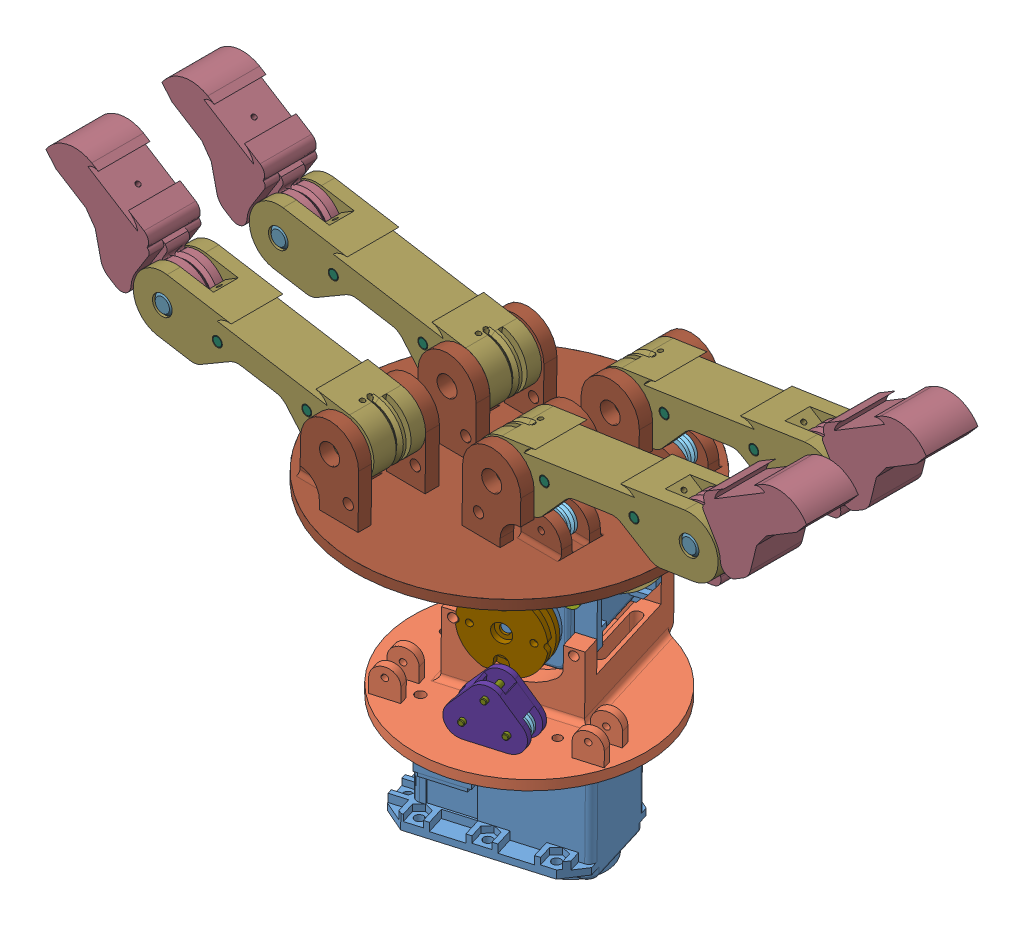
SolidWorks assembly OpenHand_v2.6, configuration 默认. Lengths in mm.
Overall size (235.63 168.54 102.71).
62 component instances, 17 part files, 48 mates.
Components (placement in the parent):
- dynamixel MX-28-1: dynamixel MX-28 [Back Off] at (-35.2758 -22.644 76.0254) x (-0.956254 0.00984 0.292372) z (0.292356 -0.003009 0.956305) size (35.6 50.71 42.77)
- 手爪手臂连接件-1: 手爪手臂连接件 [默认] at (-31.7883 -47.1811 88.258) x (0.956254 -0.00984 -0.292372) z (0.01029 0.999947 0) size (72 72 25.25)
- 手爪连接滑轮组-1: 手爪连接滑轮组 [默认] at (-84.7153 10.6727 102.6786) x (0 0.011926 -0.999929) z (1 0 0) size (37.98 14.28 12.7)
  - my_b3_t-1: my_b3_t [默认] at (-6.5452 0.3026 30) size (37.98 14.28 8.2)
  - my_b3_t-2: my_b3_t [默认] at (-6.5452 0.3026 24.7) x (-1 0 0) z (0 0 -1) size (37.98 14.28 8.2)
  - 连接销L12-4: 连接销L12 [默认] at (-20.5452 0.3787 28.3573) x (0 0 -1) z (1 0 0) size (12 1.8 1.8)
  - 连接销L12-5: 连接销L12 [默认] at (-6.5452 -6.5319 28.3573) x (0 0 -1) z (1 0 0) size (12 1.8 1.8)
  - 连接销L12-6: 连接销L12 [默认] at (7.4531 0.3475 26.3427) x (0 0 1) z (1 0 0) size (12 1.8 1.8)
  - pulley-5: pulley [默认] at (7.4531 0.3475 27.15) x (0 1 0) z (1 0 0) size (8 4.9 8)
  - pulley-6: pulley [默认] at (-20.5452 0.3787 27.15) x (0 1 0) z (1 0 0) size (8 4.9 8)
- 装配体1-2: 装配体1 [默认] at (-30.2221 0.086 58.5005) x (0.956254 -0.00984 -0.292372) z (0.292356 -0.003009 0.956305) size (35.6 28.8 14)
  - my_b4_a_t-1: my_b4_a_t [默认] at (-9.7328 -20.7064 30.35) size (35.6 28.8 14)
  - my_b4_b_t-1: my_b4_b_t [默认] at (-9.7328 -3.7131 35.55) size (35.6 12.5 5.7)
- pulley - 副本-1: pulley - 副本 [默认] at (-32.8106 -4.6684 98.0197) x (-0.120012 0.991974 0.03981) z (0.948749 0.126407 -0.289649) size (8 3 8)
- my_b1_t-3: my_b1_t [默认] at (-28.4727 -22.714 98.2786) x (0.01029 0.999947 0) z (-0.292356 0.003009 -0.956305) size (23 23 6.2)
- pulley - 副本 (2)-3: pulley - 副本 (2) [默认] at (-27.0444 10.3731 101.3236) x (0.00941 0.999952 -0.002877) z (0.292386 0 0.9563) size (10.4 4.9 10.4)
- 手爪舵机连接部分-2: 手爪舵机连接部分 [默认] at (-28.1545 15.8848 83.2704) x (0.999947 -0.01029 0) z (0 0 1) size (96 40 96)
- pulley-2: pulley [默认] at (-53.3904 23.6439 125.5553) x (0 -1 0) z (1 0 0) size (8 4.9 8)
- pulley-3: pulley [默认] at (-53.3904 23.6439 88.8154) x (0 1 0) z (1 0 0) size (8 4.9 8)
- pulley-4: pulley [默认] at (-3.1278 23.1271 107.4404) x (0 1 0) z (1 0 0) size (8 4.9 8)
- pulley-5: pulley [默认] at (-3.1278 23.1271 70.2704) x (0 1 0) z (1 0 0) size (8 4.9 8)
- 手抓-1: 手抓 [默认] at (-67.5893 118.1765 105.0764) x (-0.986609 0.163102 0) z (-0.163102 -0.986609 0) size (110.37 16.35 41.89)
  - my_finger_pp_t_A-1: my_finger_pp_t_A [默认] at (-9.7667 7.836 77.6665) size (75.23 16 18)
  - my_finger_pp_t_B-1: my_finger_pp_t_B [默认] at (23.1508 7.486 84.1655) x (0 1 0) z (-0.922593 0 0.385775) size (16 23.58 52.19)
  - 连接销R3L16-1: 连接销R3L16 [默认] at (20.4333 13.1787 77.6665) x (0 1 0) z (0.992881 0 0.11911) size (16 6 6)
  - 连接销R1.5L16-1: 连接销R1.5L16 [默认] at (3.4333 13.1787 76.1665) x (0 1 0) z (0.072413 0 0.997375) size (16 3 3)
  - 连接销R1.5L16-2: 连接销R1.5L16 [默认] at (-24.6167 13.1787 76.1665) x (0 1 0) z (0 0 1) size (16 3 3)
- 手抓-2: 手抓 [默认] at (12.5958 117.4062 91.0044) x (0.98909 0.147311 0) z (0.147311 -0.98909 0) size (110.37 16.35 41.89)
  - my_finger_pp_t_A-1: my_finger_pp_t_A [默认] at (-9.7667 7.836 77.6665) size (75.23 16 18)
  - my_finger_pp_t_B-1: my_finger_pp_t_B [默认] at (23.1508 7.486 84.1655) x (0 1 0) z (-0.922593 0 0.385775) size (16 23.58 52.19)
  - 连接销R3L16-1: 连接销R3L16 [默认] at (20.4333 13.1787 77.6665) x (0 1 0) z (0.992881 0 0.11911) size (16 6 6)
  - 连接销R1.5L16-1: 连接销R1.5L16 [默认] at (3.4333 13.1787 76.1665) x (0 1 0) z (0.072413 0 0.997375) size (16 3 3)
  - 连接销R1.5L16-2: 连接销R1.5L16 [默认] at (-24.6167 13.1787 76.1665) x (0 1 0) z (0 0 1) size (16 3 3)
- 手抓-3: 手抓 [默认] at (12.9087 117.4864 54.3344) x (0.988927 0.148402 0) z (0.148402 -0.988927 0) size (110.37 16.35 41.89)
  - my_finger_pp_t_A-1: my_finger_pp_t_A [默认] at (-9.7667 7.836 77.6665) size (75.23 16 18)
  - my_finger_pp_t_B-1: my_finger_pp_t_B [默认] at (23.1508 7.486 84.1655) x (0 1 0) z (-0.922593 0 0.385775) size (16 23.58 52.19)
  - 连接销R3L16-1: 连接销R3L16 [默认] at (20.4333 13.1787 77.6665) x (0 1 0) z (0.992881 0 0.11911) size (16 6 6)
  - 连接销R1.5L16-1: 连接销R1.5L16 [默认] at (3.4333 13.1787 76.1665) x (0 1 0) z (0.072413 0 0.997375) size (16 3 3)
  - 连接销R1.5L16-2: 连接销R1.5L16 [默认] at (-24.6167 13.1787 76.1665) x (0 1 0) z (0 0 1) size (16 3 3)
- 手抓-4: 手抓 [默认] at (-67.5893 118.1765 140.9663) x (-0.986609 0.163102 0) z (-0.163102 -0.986609 0) size (110.37 16.35 41.89)
  - my_finger_pp_t_A-1: my_finger_pp_t_A [默认] at (-9.7667 7.836 77.6665) size (75.23 16 18)
  - my_finger_pp_t_B-1: my_finger_pp_t_B [默认] at (23.1508 7.486 84.1655) x (0 1 0) z (-0.922593 0 0.385775) size (16 23.58 52.19)
  - 连接销R3L16-1: 连接销R3L16 [默认] at (20.4333 13.1787 77.6665) x (0 1 0) z (0.992881 0 0.11911) size (16 6 6)
  - 连接销R1.5L16-1: 连接销R1.5L16 [默认] at (3.4333 13.1787 76.1665) x (0 1 0) z (0.072413 0 0.997375) size (16 3 3)
  - 连接销R1.5L16-2: 连接销R1.5L16 [默认] at (-24.6167 13.1787 76.1665) x (0 1 0) z (0 0 1) size (16 3 3)
- dynamixel MX-28-3: dynamixel MX-28 [Back Off] at (-21.9354 -65.5335 85.1881) x (-0.292356 0.003009 -0.956305) z (-0.01029 -0.999947 0) size (35.6 50.71 42.77)
- 舵机带动滑轮组-2: 舵机带动滑轮组 [默认] at (-25.0225 -35.0923 91.0124) x (0.956254 -0.00984 -0.292372) z (0.292356 -0.003009 0.956305) size (21 16.39 10)
  - pulley-1: pulley [默认] at (-8.534 -4.6935 16.5468) x (1 0 0) z (0 -1 0) size (8 4.9 8)
  - pulley-2: pulley [默认] at (2.4752 -4.6578 16.5468) x (1 0 0) z (0 -1 0) size (8 4.9 8)
  - 连接销L10-1: 连接销L10 [默认] at (-8.5248 -4.6578 16.5541) x (0 0 -1) z (1 0 0) size (10 1.8 1.8)
  - 连接销L10-2: 连接销L10 [默认] at (2.4752 -4.6578 16.5541) x (0 0 -1) z (0 1 0) size (10 1.8 1.8)
  - 连接销L10-3: 连接销L10 [默认] at (-3.0248 2.9552 16.5541) x (0 0 -1) z (1 0 0) size (10 1.8 1.8)
  - my_b5_t-1: my_b5_t [默认] at (0.0252 -7.9078 11.8968) size (21 16.39 7.1)
  - my_b5_t-2: my_b5_t [默认] at (-6.0748 -7.9078 20.7968) x (-1 0 0) z (0 0 -1) size (21 16.39 7.1)
- 手爪连接滑轮组-6: 手爪连接滑轮组 [默认] at (-28.793 9.0308 81.0073) x (0.000123 0.011926 -0.999929) z (0.999947 -0.01029 0) size (37.98 14.28 12.7)
  - my_b3_t-1: my_b3_t [默认] at (-6.5452 0.3026 30) size (37.98 14.28 8.2)
  - my_b3_t-2: my_b3_t [默认] at (-6.5452 0.3026 24.7) x (-1 0 0) z (0 0 -1) size (37.98 14.28 8.2)
  - 连接销L12-4: 连接销L12 [默认] at (-20.5452 0.3787 28.3573) x (0 0 -1) z (1 0 0) size (12 1.8 1.8)
  - 连接销L12-5: 连接销L12 [默认] at (-6.5452 -6.5319 28.3573) x (0 0 -1) z (1 0 0) size (12 1.8 1.8)
  - 连接销L12-6: 连接销L12 [默认] at (7.4531 0.3475 26.3427) x (0 0 1) z (1 0 0) size (12 1.8 1.8)
  - pulley-5: pulley [默认] at (7.4531 0.3475 27.15) x (0 1 0) z (1 0 0) size (8 4.9 8)
  - pulley-6: pulley [默认] at (-20.5452 0.3787 27.15) x (0 1 0) z (1 0 0) size (8 4.9 8)
Mates (geometry in assembly coordinates):
- 重合5: coincident anti-aligned: plane of dynamixel MX-28-1 through (-39.6612 -22.5988 61.6808) normal (-0.292356 0.003009 -0.956305); plane of 手爪手臂连接件-1 through (-56.7082 -24.9235 66.885) normal (0.292356 -0.003009 0.956305)
- 同心7: concentric aligned: circle of dynamixel MX-28-1; circle of 手爪手臂连接件-1
- 重合13: coincident anti-aligned: plane of dynamixel MX-28-1 through (-52.2549 -34.4699 62.6179) normal (-0.01029 -0.999947 0); plane of 手爪手臂连接件-1 through (-31.6596 -34.6818 88.258) normal (0.01029 0.999947 0)
- 重合17: coincident anti-aligned: plane of dynamixel MX-28-1 through (-30.0865 -22.6974 92.9998) normal (0.292356 -0.003009 0.956305); plane of 装配体1-2/my_b4_a_t-1 through (-30.0652 -20.623 92.9998) normal (-0.292356 0.003009 -0.956305)
- 同心16: concentric anti-aligned: circle of dynamixel MX-28-1; circle of 装配体1-2/my_b4_b_t-1
- 同心17: concentric anti-aligned: circle of dynamixel MX-28-1; circle of 装配体1-2/my_b4_b_t-1
- 同心20: concentric aligned: circle of 装配体1-2/my_b4_b_t-1; circle of pulley - 副本-1
- 同心26: concentric anti-aligned: circle of dynamixel MX-28-1; circle of my_b1_t-3
- 重合31: coincident anti-aligned: plane of dynamixel MX-28-1 through (-29.2767 -22.7057 95.6487) normal (0.292356 -0.003009 0.956305); plane of my_b1_t-3 through (-29.2767 -22.7057 95.6487) normal (-0.292356 0.003009 -0.956305)
- 重合37: coincident anti-aligned: plane of 装配体1-2/my_b4_a_t-1 through (-29.3489 -20.6304 95.3427) normal (0.292356 -0.003009 0.956305); plane of pulley - 副本-1 through (-33.3691 -3.6719 96.6251) normal (-0.292356 0.003009 -0.956305)
- 同心30: concentric anti-aligned: circle of 装配体1-2/my_b4_a_t-1; circle of pulley - 副本 (2)-3
- 重合41: coincident anti-aligned: plane of 装配体1-2/my_b4_a_t-1 through (-28.2701 -9.6833 89.6098) normal (-0.956254 0.00984 0.292372); plane of pulley - 副本 (2)-3 through (-24.6921 11.3489 100.6044) normal (0.956254 -0.00984 -0.292372)
- 同心32: concentric aligned: circle of 手爪舵机连接部分-2; circle of pulley-2
- 重合44: coincident anti-aligned: plane of 手爪舵机连接部分-2 through (19.8697 17.8907 128.0053) normal (0 0 -1); plane of pulley-2 through (-53.3904 22.6439 128.0053) normal (0 0 1)
- 同心33: concentric anti-aligned: circle of 手爪舵机连接部分-2; circle of pulley-3
- 同心34: concentric anti-aligned: circle of 手爪舵机连接部分-2; circle of pulley-4
- 同心35: concentric anti-aligned: circle of 手爪舵机连接部分-2; circle of pulley-5
- 重合48: coincident anti-aligned: plane of 手爪舵机连接部分-2 through (-76.1272 18.8786 109.8904) normal (0 0 -1); plane of pulley-4 through (-3.1278 24.1271 109.8904) normal (0 0 1)
- 重合49: coincident anti-aligned: plane of 手爪舵机连接部分-2 through (-76.1272 18.8786 67.8204) normal (0 0 1); plane of pulley-5 through (-3.1278 24.1271 67.8204) normal (0 0 -1)
- 重合50: coincident anti-aligned: plane of 手爪舵机连接部分-2 through (19.8697 17.8907 86.3654) normal (0 0 1); plane of pulley-3 through (-53.3904 24.6439 86.3654) normal (0 0 -1)
- 同心36: concentric anti-aligned: circle of 手爪舵机连接部分-2; circle of ?
- 重合51: coincident anti-aligned: plane of 手爪舵机连接部分-2 through (19.9494 25.6353 117.1303) normal (0 0 1); plane of 手抓-4/my_finger_pp_t_A-1 through (-51.6004 32.7584 117.1303) normal (0 0 -1)
- 同心37: concentric aligned: circle of 手爪舵机连接部分-2; circle of ?
- 重合52: coincident anti-aligned: plane of 手爪舵机连接部分-2 through (19.9494 25.6353 97.2404) normal (0 0 -1); plane of 手抓-1/my_finger_pp_t_A-1 through (-51.6004 32.7584 97.2404) normal (0 0 1)
- 同心38: concentric: circle of 手爪舵机连接部分-2; circle of ?
- 重合53: coincident anti-aligned: plane of 手爪舵机连接部分-2 through (41.5357 17.6678 62.1704) normal (0 0 1); plane of 手抓-3/my_finger_pp_t_A-1 through (-4.3495 32.3156 62.1704) normal (0 0 -1)
- 同心39: concentric aligned: circle of 手爪舵机连接部分-2; circle of ?
- 重合54: coincident anti-aligned: plane of 手爪舵机连接部分-2 through (-56.6959 18.6786 98.8404) normal (0 0 1); plane of 手抓-2/my_finger_pp_t_A-1 through (-4.7564 32.2545 98.8404) normal (0 0 -1)
- 相切6: tangent anti-aligned: cylinder of 手爪舵机连接部分-2 through (-3.0992 21.1273 101.1904) axis (0 0 1) radius 6.25; cylinder of 手抓-2/my_finger_pp_t_A-1 through (-4.7564 32.2545 114.8404) axis (0 0 -1) radius 5
- 同心47: concentric anti-aligned: circle of 手爪手臂连接件-1; circle of dynamixel MX-28-3
- 重合63: coincident anti-aligned: plane of dynamixel MX-28-1 through (-30.8905 -22.6891 90.3699) normal (0.292356 -0.003009 0.956305); plane of 手爪舵机连接部分-2 through (-26.4878 4.367 89.1091) normal (-0.292356 0.003009 -0.956305)
- 重合65: coincident anti-aligned: plane of dynamixel MX-28-1 through (-18.9336 15.7899 84.7442) normal (0.01029 0.999947 0); plane of 手爪舵机连接部分-2 through (-28.1545 15.8848 83.2704) normal (-0.01029 -0.999947 0)
- 同心48: concentric aligned: circle of dynamixel MX-28-1; circle of 手爪舵机连接部分-2
- 重合66: coincident anti-aligned: plane of dynamixel MX-28-1 through (-39.6612 -22.5988 61.6808) normal (-0.292356 0.003009 -0.956305); plane of 手爪舵机连接部分-2 through (-35.2585 4.4573 60.4199) normal (0.292356 -0.003009 0.956305)
- 重合67: coincident anti-aligned: plane of dynamixel MX-28-1 through (-39.6612 -22.5988 61.6808) normal (-0.292356 0.003009 -0.956305); plane of 手爪舵机连接部分-2 through (-35.2585 4.4573 60.4199) normal (0.292356 -0.003009 0.956305)
- 同心49: concentric anti-aligned: circle of 手爪手臂连接件-1; circle of dynamixel MX-28-3
- 重合68: coincident anti-aligned: plane of 手爪手臂连接件-1 through (-31.7625 -44.6813 88.258) normal (0.01029 0.999947 0); plane of 舵机带动滑轮组-2/my_b5_t-2 through (-17.2011 -44.8311 108.4555) normal (-0.01029 -0.999947 0)
- 同心50: concentric aligned: circle of 手爪舵机连接部分-2; circle of 手抓-4/my_finger_pp_t_A-1
- 同心52: concentric anti-aligned: circle of 手爪舵机连接部分-2; circle of 手抓-3/my_finger_pp_t_A-1
- 同心53: concentric aligned: circle of 手爪舵机连接部分-2; circle of 手抓-1/my_finger_pp_t_A-1
- 重合69: coincident anti-aligned: plane of 手爪手臂连接件-1 through (-31.8217 -50.431 88.258) normal (-0.01029 -0.999947 0); plane of dynamixel MX-28-3 through (-21.781 -50.5343 85.1881) normal (0.01029 0.999947 0)
- 同心54: concentric aligned: cylinder of dynamixel MX-28-1 through (-29.8614 -22.6997 93.7361) axis (0.292356 -0.003009 0.956305) radius 11; cylinder of my_b1_t-3 through (-29.2767 -22.7057 95.6487) axis (0.292356 -0.003009 0.956305) radius 11.5
- 同心55: concentric aligned: cylinder of dynamixel MX-28-1 through (-29.8614 -22.6997 93.7361) axis (0.292356 -0.003009 0.956305) radius 11; cylinder of my_b1_t-3 through (-29.2767 -22.7057 95.6487) axis (0.292356 -0.003009 0.956305) radius 11.5
- 相切14: tangent anti-aligned: cylinder of 手爪舵机连接部分-2 through (-3.0992 21.1273 101.1904) axis (0 0 1) radius 6.25; cylinder of 手抓-2/my_finger_pp_t_A-1 through (-4.7564 32.2545 114.8404) axis (0 0 -1) radius 5
- 相切16: tangent anti-aligned: cylinder of 手爪舵机连接部分-2 through (-3.0992 21.1273 101.1904) axis (0 0 1) radius 6.25; plane of 手抓-2/my_finger_pp_t_A-1 through (-11.0325 26.2646 114.8404) normal (0.147311 -0.98909 0)
- 相切18: tangent anti-aligned: cylinder of 手爪舵机连接部分-2 through (-3.0992 21.1273 76.5204) axis (0 0 -1) radius 6.25; plane of 手抓-3/my_finger_pp_t_A-1 through (-10.619 26.3188 78.1704) normal (0.148402 -0.988927 0)
- 相切20: tangent anti-aligned: cylinder of 手爪舵机连接部分-2 through (-53.3465 21.6443 131.3593) axis (0 0 -1) radius 6.25; plane of 手抓-4/my_finger_pp_t_A-1 through (-45.4209 26.6689 117.1303) normal (-0.163102 -0.986609 0)
- 相切22: tangent anti-aligned: cylinder of 手爪舵机连接部分-2 through (-53.3465 21.6443 83.0114) axis (0 0 1) radius 6.25; plane of 手抓-1/my_finger_pp_t_A-1 through (-45.4209 26.6689 81.2404) normal (-0.163102 -0.986609 0)
